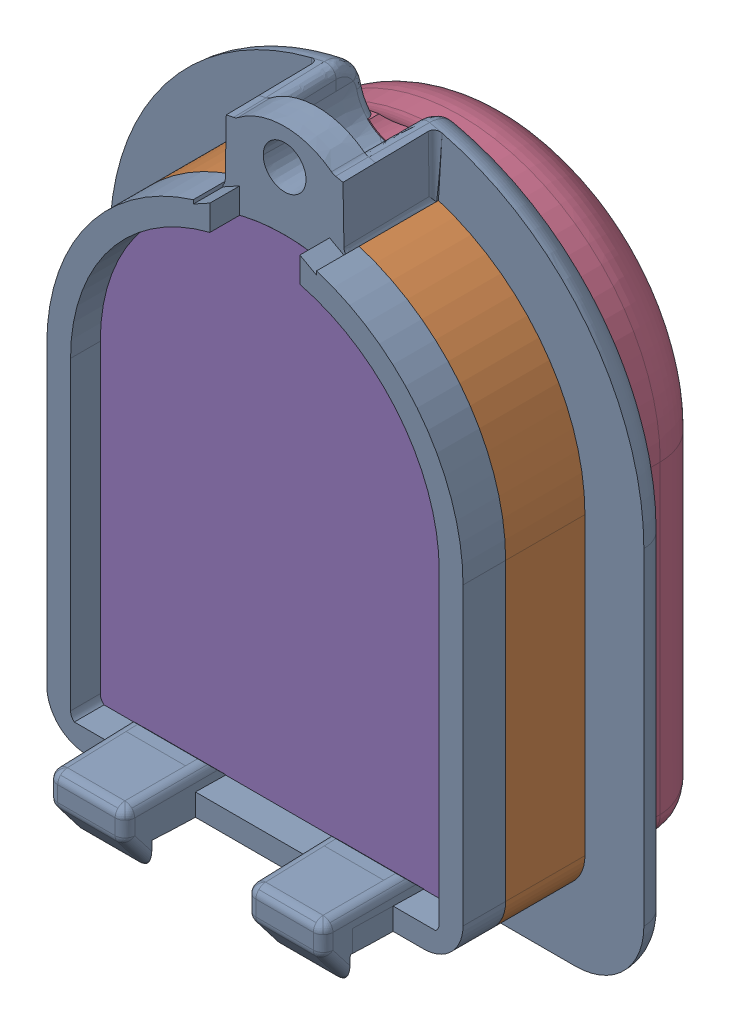
SolidWorks assembly Conti, configuration 默认. Lengths in mm.
Overall size (26.95 34.26 16.66).
6 component instances, 6 part files, 14 mates.
Components (placement in the parent):
- ContiOriginBody-1: ContiOriginBody [默认] at (-2.213 7.3799 -8.324) size (26.95 34.26 11.2)
- ContiTransBody-1: ContiTransBody [默认] at (-2.213 7.3799 -8.324) size (21 26.93 4)
- ContiInsideSKin-1: ContiInsideSKin [默认] at (-2.213 4.0799 -7.824) x (-1 0 0) z (0 0 -1) size (18.6 25.2 5.2)
- ContioutSkin-1: ContioutSkin [默认] at (-2.213 4.0799 -7.824) x (-1 0 0) z (0 0 -1) size (21.8 28.5 6)
- ContiLens-1: ContiLens [默认] at (-2.213 7.3799 -7.824) size (18.6 25.2 5.65)
- ConMarker-1: ConMarker [默认] at (-8.213 -6.5201 -13.024) size (13 20.5 0.4)
Mates (geometry in assembly coordinates):
- 重合1: coincident anti-aligned: plane of OriginBody-1 through (-2.213 7.3799 -6.824) normal (0 0 1); plane of TransBody-1 through (7.137 -9.7124 -6.824) normal (0 0 -1)
- 同心1: concentric aligned: cylinder of OriginBody-1 through (-2.213 7.3799 -0.674) axis (0 0 -1) radius 10.5; cylinder of TransBody-1 through (-2.213 7.3799 -0.674) axis (0 0 -1) radius 10.5
- 重合2: coincident aligned: plane of OriginBody-1 through (8.287 7.3799 -0.674) normal (1 0 0); plane of TransBody-1 through (8.287 7.3799 -0.674) normal (1 0 0)
- 重合3: coincident anti-aligned: plane of TransBody-1 through (-2.213 -8.5201 48.523) normal (0 1 0); plane of Lens-1 through (-11.513 -8.5201 -2.674) normal (0 -1 0)
- 同心2: concentric aligned: cylinder of TransBody-1 through (-2.213 7.3799 48.523) axis (0 0 -1) radius 9.3; cylinder of Lens-1 through (-2.213 7.3799 -2.674) axis (0 0 -1) radius 9.3
- 重合5: coincident anti-aligned: plane of NewInsideSkin-1 through (-11.013 -8.0201 -8.324) normal (0 0 1); plane of Lens-1 through (-2.213 7.3799 -8.324) normal (0 0 -1)
- 重合6: coincident anti-aligned: plane of NewInsideSkin-1 through (-11.013 -8.0201 -13.524) normal (0 0 -1); plane of outSkin-1 through (-11.013 -8.0201 -13.524) normal (0 0 1)
- 同心4: concentric aligned: cylinder of NewInsideSkin-1 through (-2.213 7.3799 -13.524) axis (0 0 1) radius 9.3; cylinder of outSkin-1 through (-2.213 7.3799 -13.524) axis (0 0 1) radius 9.3
- 平行2: parallel aligned: plane of NewInsideSkin-1 through (-11.013 -8.5201 -13.524) normal (0 -1 0); plane of outSkin-1 through (-11.013 -9.3201 -13.524) normal (0 -1 0)
- 重合10: coincident aligned: plane of ContiInsideSKin-1 through (-11.013 -8.0201 -13.524) normal (0 0 -1); plane of ConMarker-1 through (-8.213 -6.5201 -13.524) normal (0 0 -1)
- 宽度2: width anti-aligned: plane of ContiInsideSKin-1 through (-11.513 7.3799 -13.524) normal (-1 0 0); plane of ContiInsideSKin-1 through (7.087 -8.0201 -13.524) normal (1 0 0); plane of ConMarker-1 through (4.287 -6.5201 -13.124) normal (1 0 0); plane of ConMarker-1 through (-8.713 4.465 -13.524) normal (-1 0 0)
- 重合11: coincident: line of ContiInsideSKin-1 through (5.087 -6.5201 -13.524) axis (-1 0 0); plane of ConMarker-1 through (-8.213 -6.5201 -13.124) normal (0 -1 0)
- 同心5: concentric aligned: cone of OriginBody-1 through (-2.213 19.6299 -3.824) axis (0 0 1); cylinder of outSkin-1 through (-2.213 19.6299 -18.324) axis (0 0 1) radius 2.0018
- 重合12: coincident anti-aligned: plane of OriginBody-1 through (-11.013 -8.0201 -7.824) normal (0 0 -1); plane of outSkin-1 through (-11.013 -8.0201 -8.324) normal (0 0 1)
